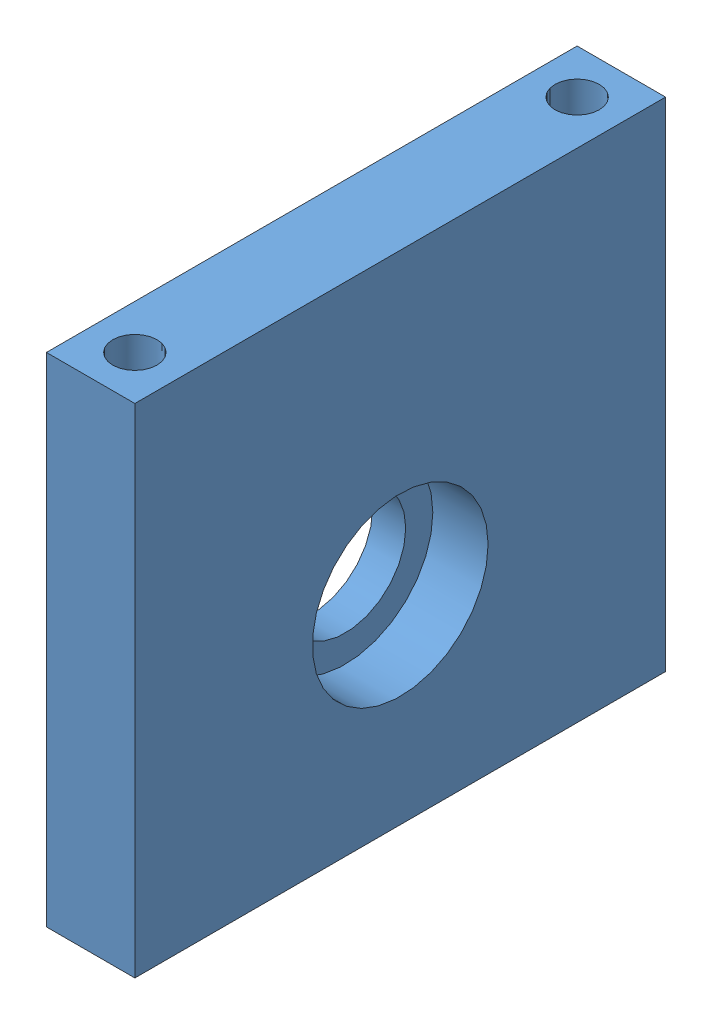
SolidWorks assembly Assemblage Axe BRS, configuration Défaut. Lengths in mm.
Overall size (8 45 48).
2 component instances, 2 part files, 2 mates.
Components (placement in the parent):
- Support Axe Roue BRS-1: Support Axe Roue BRS [Défaut] at (13.8411 -10.182 72) size (8 45 48)
- Roulement a bille D16 D5 BRS-1: Roulement a bille D16 D5 BRS [Défaut] at (16.8411 7.818 48) x (0 0 -1) z (1 0 0) (suppressed, hidden)
Mates (geometry in assembly coordinates):
- Coaxiale1: concentric anti-aligned: cylinder of Support Axe Roue BRS-1 through (11.8411 7.818 48) axis (1 0 0) radius 7.95; cylinder of Roulement a bille D16 D5 BRS-1 through (21.8411 7.818 48) axis (-1 0 0) radius 8
- Coïncidente1: coincident aligned: plane of Support Axe Roue BRS-1 through (21.8411 34.818 72) normal (1 0 0); plane of Roulement a bille D16 D5 BRS-1 through (21.8411 7.818 48) normal (1 0 0)
